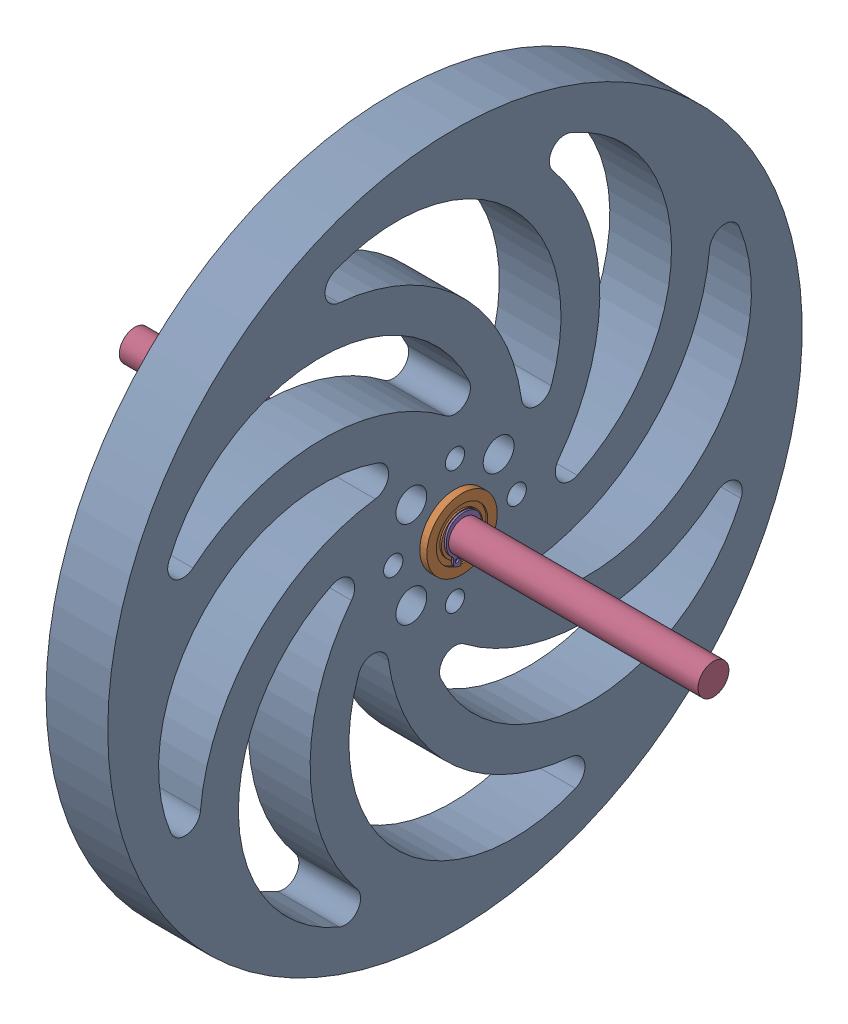
SolidWorks assembly Laser_Sprocket-Passive-Dx1, configuration Default. Lengths in mm.
Overall size (75 90 90).
6 component instances, 4 part files, 9 mates.
Components (placement in the parent):
- Laser-Sprocket_Center-Passive-Dx-1: Laser-Sprocket_Center-Passive-Dx [Default] at (26.0533 23.785 -47.0741) size (8 90 90)
- Bearing-4mm-Dx-1: Bearing-4mm-Dx [Default] at (34.9674 23.785 -47.0741) size (3.17 9.12 9.12)
- Bearing-4mm-Dx-2: Bearing-4mm-Dx [Default] at (25.1392 23.785 -47.0741) x (-1 0 0) z (0 0 -1) size (3.17 9.12 9.12)
- Shaft-4mm-Dx-1: Shaft-4mm-Dx [Default] at (-7.4467 23.785 -47.0741) x (1 0 0) z (0 -0.425008 -0.90519) size (75 4 4)
- msh_4-Dx-1: msh_4-Dx [Default] at (35.0923 23.785 -47.0741) x (0 0 1) z (0 1 0) size (4.59 0.25 5.77)
- msh_4-Dx-2: msh_4-Dx [Default] at (25.0143 23.785 -47.0741) x (0 1 0) z (0 0 1) size (4.59 0.25 5.77)
Mates (geometry in assembly coordinates):
- Concentrico1: concentric anti-aligned: circle of Laser-Sprocket_Center-Passive-Dx-1; circle of Bearing-4mm-Dx-2
- Coincidente1: coincident anti-aligned: plane of Laser-Sprocket_Center-Passive-Dx-1 through (26.0533 23.785 -47.0741) normal (-1 0 0); plane of Bearing-4mm-Dx-2 through (26.0533 28.3445 -47.0741) normal (1 0 0)
- Coincidente2: coincident anti-aligned: plane of Laser-Sprocket_Center-Passive-Dx-1 through (34.0533 23.785 -47.0741) normal (1 0 0); plane of Bearing-4mm-Dx-1 through (34.0533 28.3445 -47.0741) normal (-1 0 0)
- Concentrico2: concentric aligned: circle of Laser-Sprocket_Center-Passive-Dx-1; circle of Bearing-4mm-Dx-1
- Concentrico3: concentric anti-aligned: circle of Bearing-4mm-Dx-2; circle of Shaft-4mm-Dx-1
- Coincidente3: coincident anti-aligned: plane of Bearing-4mm-Dx-1 through (34.9673 25.9351 -47.0741) normal (1 0 0); plane of msh_4-Dx-1 through (34.9673 20.6168 -47.5241) normal (-1 0 0)
- Concentrico4: concentric anti-aligned: circle of Bearing-4mm-Dx-1; circle of msh_4-Dx-1
- Concentrico5: concentric aligned: circle of Shaft-4mm-Dx-1; circle of msh_4-Dx-2
- Coincidente4: coincident anti-aligned: plane of Bearing-4mm-Dx-2 through (25.1393 25.9351 -47.0741) normal (-1 0 0); plane of msh_4-Dx-2 through (25.1393 23.335 -50.2423) normal (1 0 0)
